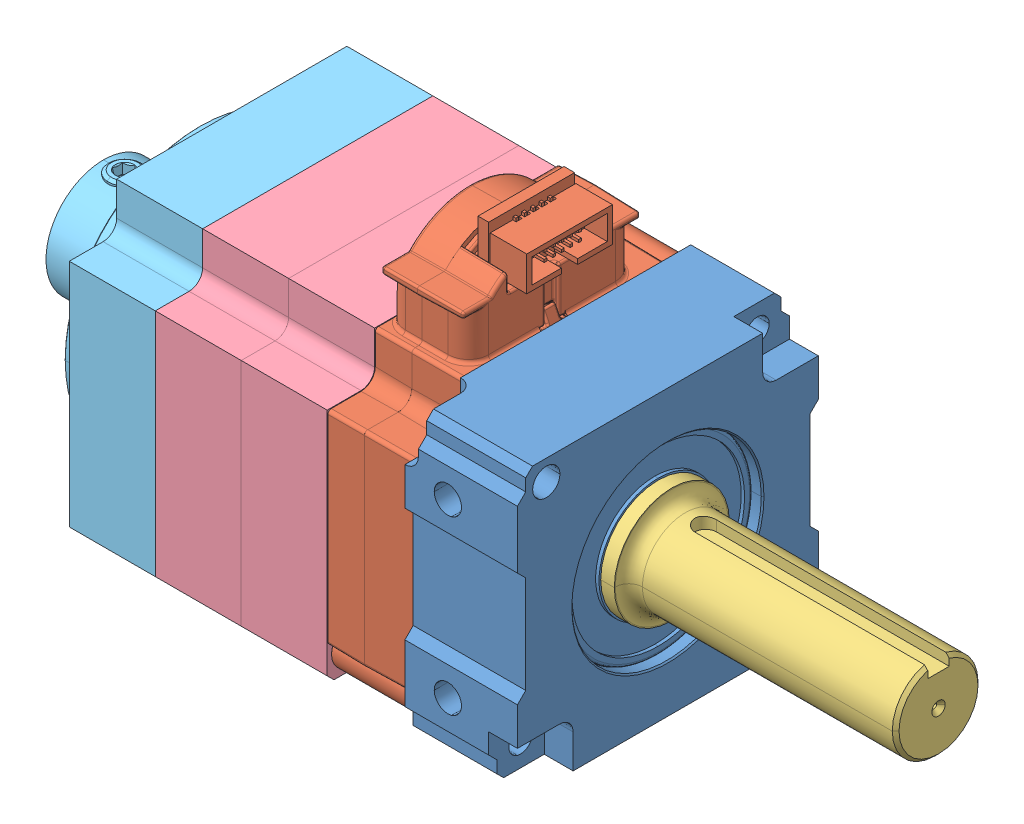
SolidWorks assembly Gearbox Assembly, configuration Default. Lengths in mm.
Overall size (123.35 56.32 44.45).
6 component instances, 5 part files, 6 mates.
Components (placement in the parent):
- Output Housing-2: Output Housing [Default] at (64.8023 -0.856 18.2213) x (1 0 0) z (0 -1 0) size (75.7 44.45 56.32)
  - Housing-1: Housing [Default] at (19.8785 -6.4219 -11.5232) size (18.13 44.45 42)
  - Encoder.step-1: Encoder.step [Default] at (12.6785 15.8031 -11.5232) x (0 0 1) z (-1 0 0) size (56.32 42 21.21)
  - Gearbox_output_shaft-1: Gearbox_output_shaft [Default] at origin size (63.51 17 17)
- Ring Gears-1: Ring Gears [Default] at (71.9808 10.6671 11.7994) x (1 0 0) z (0 -1 0) size (32.2 42 42)
- Ring Gear Stage 3-1: Ring Gear Stage 3 [Default] at (59.2808 10.6671 11.7994) x (1 0 0) z (0 -1 0) size (28.65 42 42)
Mates (geometry in assembly coordinates):
- Concentric1: concentric aligned: cylinder of Output Housing-2/Housing-1 through (97.0418 28.1671 16.5244) axis (1 0 0) radius 1.7272; cylinder of Ring Gears-1 through (59.2808 28.1671 16.5244) axis (1 0 0) radius 2.1526
- Concentric2: concentric aligned: cylinder of Output Housing-2/Housing-1 through (97.0418 -6.8329 51.5244) axis (1 0 0) radius 1.7272; cylinder of Ring Gears-1 through (71.9808 -6.8329 51.5244) axis (1 0 0) radius 2.1526
- Coincident1: coincident anti-aligned: plane of Output Housing-2/Encoder.step-1 through (71.9808 10.6671 34.0244) normal (-1 0 0); plane of Ring Gears-1 through (71.9808 31.6671 13.0244) normal (1 0 0)
- Concentric3: concentric aligned: cylinder of Ring Gears-1 through (59.2808 28.1671 16.5244) axis (1 0 0) radius 2.1526; cylinder of Ring Gear Stage 3-1 through (46.5808 28.1671 16.5244) axis (1 0 0) radius 2.1526
- Concentric4: concentric aligned: cylinder of Ring Gears-1 through (59.2808 -6.8329 51.5244) axis (1 0 0) radius 2.1526; cylinder of Ring Gear Stage 3-1 through (46.5808 -6.8329 51.5244) axis (1 0 0) radius 2.1526
- Coincident2: coincident anti-aligned: plane of Ring Gears-1 through (46.5808 31.6671 13.0244) normal (-1 0 0); plane of Ring Gear Stage 3-1 through (46.5808 31.6671 13.0244) normal (1 0 0)
